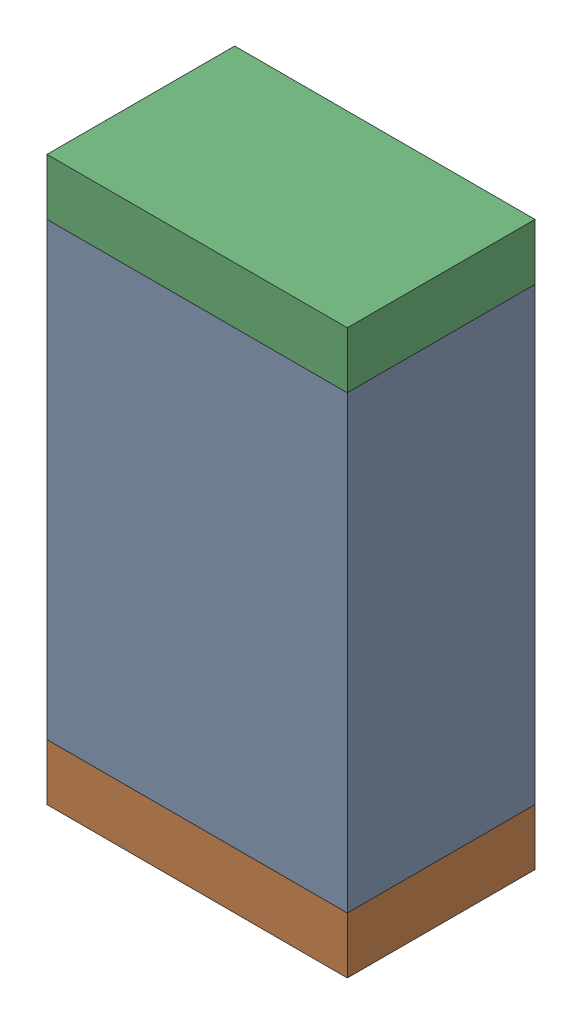
SolidWorks assembly R9, configuration Default. Lengths in mm.
Overall size (0.8 1.5 0.5).
6 component instances, 2 part files, 0 mates.
Components (placement in the parent):
- 810156976-1: 810156976 [Default] at (129.55 36.25 0) size (0.8 1.2 0.5)
  - Extruded_6-1: Extruded_6 [Default] at origin size (0.8 1.2 0.5)
- 810156592-1: 810156592 [Default] at (129.55 35.575 0) size (0.8 0.15 0.5)
  - Extruded_7-1: Extruded_7 [Default] at origin size (0.8 0.15 0.5)
- 810156592-2: 810156592 [Default] at (129.55 36.925 0) size (0.8 0.15 0.5)
  - Extruded_7-1: Extruded_7 [Default] at origin size (0.8 0.15 0.5)
